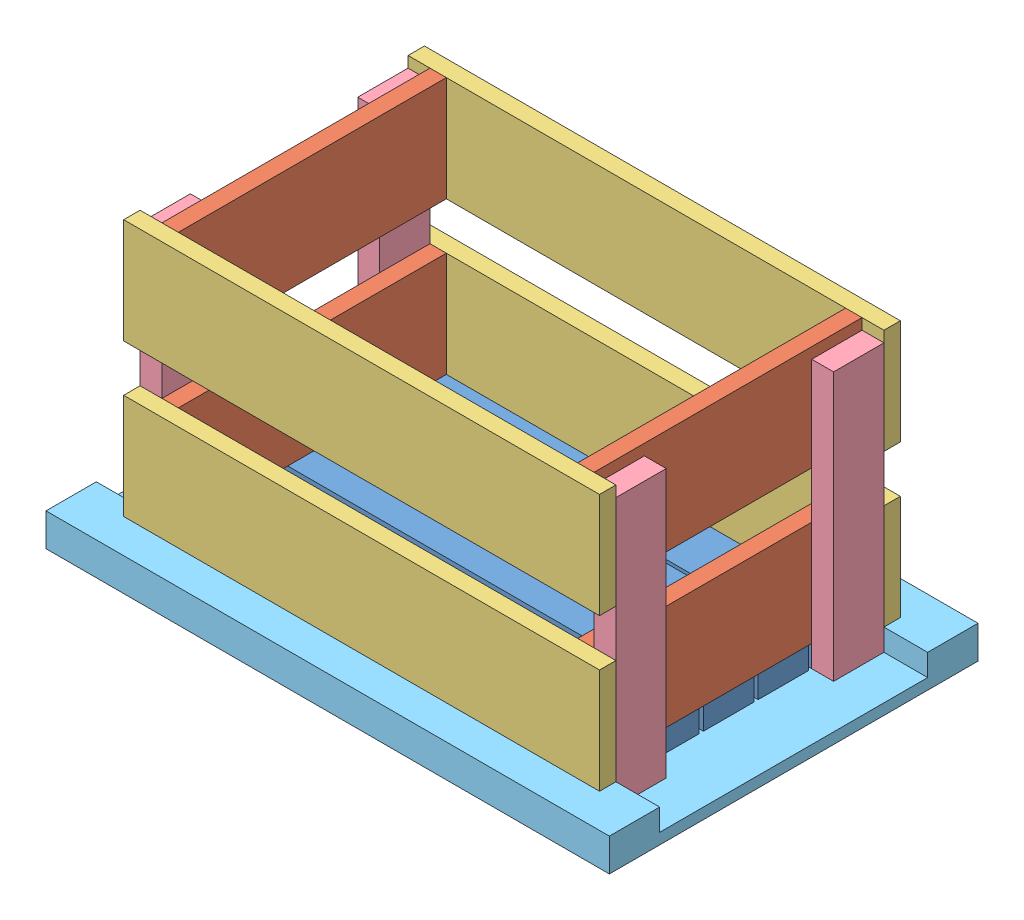
SolidWorks assembly Mal-assembly, configuration Default. Lengths in mm.
Overall size (515 265 337).
43 component instances, 6 part files, 4 mates.
Components (placement in the parent):
- Vinkasse-1: Vinkasse [Default] at (41.6987 392.7741 284.9585) size (435 265 275)
  - Bunnplank-1: Bunnplank [Default] at (0 -149 222) x (0 0 1) z (0 1 0) size (46 395 20)
  - Bunnplank-10: Bunnplank [Default] at (0 -149 23) x (0 0 1) z (0 1 0) size (46 395 20)
  - Vegg-kortside-1: Vegg-kortside [Default] at (387.5 48 245) x (0 1 0) z (-1 0 0) size (96 245 15)
  - Vegg-langside-1: Vegg-langside [Default] at (-20 48 -7.5) x (0 -1 0) z (0 0 1) size (96 435 15)
  - Vegg-langside-2: Vegg-langside [Default] at (415 48 252.5) x (0 1 0) z (0 0 1) size (96 435 15)
  - Vegg-kortside-3: Vegg-kortside [Default] at (7.5 48 0) x (0 1 0) z (1 0 0) size (96 245 15)
  - Vertikal_Stender-1: Vertikal_Stender [Default] at (405 -169 23) x (0 0 1) z (-1 0 0) size (46 255 20)
  - Vertikal_Stender-2: Vertikal_Stender [Default] at (405 -169 222) x (0 0 1) z (-1 0 0) size (46 255 20)
  - Vertikal_Stender-3: Vertikal_Stender [Default] at (-10 -169 222) x (0 0 -1) z (1 0 0) size (46 255 20)
  - Vertikal_Stender-4: Vertikal_Stender [Default] at (-10 -169 23) x (0 0 -1) z (1 0 0) size (46 255 20)
  - Vegg-kortside-5: Vegg-kortside [Default] at (7.5 -91 0) x (0 1 0) z (1 0 0) size (96 245 15)
  - Vegg-langside-3: Vegg-langside [Default] at (415 -91 252.5) x (0 1 0) z (0 0 1) size (96 435 15)
  - Vegg-langside-4: Vegg-langside [Default] at (-20 -91 -7.5) x (0 -1 0) z (0 0 1) size (96 435 15)
  - Vegg-kortside-6: Vegg-kortside [Default] at (387.5 -91 245) x (0 1 0) z (-1 0 0) size (96 245 15)
  - Dahls-1: Dahls [Default] at (41.8133 71.3082 215.5) size (59 225 59) (hidden)
  - Dahls-2: Dahls [Default] at (41.8133 71.3082 154) size (59 225 59) (hidden)
  - Dahls-3: Dahls [Default] at (41.8133 71.3082 92.5) size (59 225 59) (hidden)
  - Dahls-4: Dahls [Default] at (41.8133 71.3082 31) size (59 225 59) (hidden)
  - Dahls-5: Dahls [Default] at (103.3133 71.3082 215.5) size (59 225 59) (hidden)
  - Dahls-6: Dahls [Default] at (103.3133 71.3082 154) size (59 225 59) (hidden)
  - Dahls-7: Dahls [Default] at (103.3133 71.3082 92.5) size (59 225 59) (hidden)
  - Dahls-8: Dahls [Default] at (103.3133 71.3082 31) size (59 225 59) (hidden)
  - Dahls-9: Dahls [Default] at (164.8133 71.3082 215.5) size (59 225 59) (hidden)
  - Dahls-10: Dahls [Default] at (164.8133 71.3082 154) size (59 225 59) (hidden)
  - Dahls-11: Dahls [Default] at (164.8133 71.3082 92.5) size (59 225 59) (hidden)
  - Dahls-12: Dahls [Default] at (164.8133 71.3082 31) size (59 225 59) (hidden)
  - Dahls-13: Dahls [Default] at (226.3133 71.3082 215.5) size (59 225 59) (hidden)
  - Dahls-14: Dahls [Default] at (226.3133 71.3082 154) size (59 225 59) (hidden)
  - Dahls-15: Dahls [Default] at (226.3133 71.3082 92.5) size (59 225 59) (hidden)
  - Dahls-16: Dahls [Default] at (226.3133 71.3082 31) size (59 225 59) (hidden)
  - Dahls-17: Dahls [Default] at (287.8133 71.3082 215.5) size (59 225 59) (hidden)
  - Dahls-18: Dahls [Default] at (287.8133 71.3082 154) size (59 225 59) (hidden)
  - Dahls-19: Dahls [Default] at (287.8133 71.3082 92.5) size (59 225 59) (hidden)
  - Dahls-20: Dahls [Default] at (287.8133 71.3082 31) size (59 225 59) (hidden)
  - Dahls-21: Dahls [Default] at (349.3133 71.3082 215.5) size (59 225 59) (hidden)
  - Dahls-22: Dahls [Default] at (349.3133 71.3082 154) size (59 225 59) (hidden)
  - Dahls-23: Dahls [Default] at (349.3133 71.3082 92.5) size (59 225 59) (hidden)
  - Dahls-24: Dahls [Default] at (349.3133 71.3082 31) size (59 225 59) (hidden)
  - Bunnplank-11: Bunnplank [Default] at (0 -149 172) x (0 0 1) z (0 1 0) size (46 395 20)
  - Bunnplank-12: Bunnplank [Default] at (0 -149 122) x (0 0 1) z (0 1 0) size (46 395 20)
  - Bunnplank-13: Bunnplank [Default] at (0 -149 72) x (0 0 1) z (0 1 0) size (46 395 20)
- Part1-1: Part1 [Default] at (31.6987 223.7741 506.9585) x (0 0 1) z (0 -1 0) size (337 515 30)
Mates (geometry in assembly coordinates):
- InPlace1: in place: plane of Vinkasse-1/Vertikal_Stender-3 through (31.6987 223.7741 506.9585) normal (0 -1 0); plane of ? through (0 223.7741 0) normal (0 -1 0); moOrthogonalPlaneRef_w of Vinkasse-1/Vertikal_Stender-3 through (31.6987 223.7741 506.9585) normal (0 -1 0); plane of ? through (0 223.7741 0) normal (0 0 -1); plane of Vinkasse-1/Vertikal_Stender-3 through (31.6987 223.7741 506.9585) normal (0 -1 0); plane of ? through (0 223.7741 0) normal (-1 0 0); plane of Vinkasse-1/Vertikal_Stender-3 through (31.6987 223.7741 506.9585) normal (0 -1 0); unknown of Part1-1
- Coincident1: coincident aligned: plane of ?; plane of ?
- Coincident2: coincident aligned: moOrthogonalPlaneRef_w of Vinkasse-1/Vertikal_Stender-3 through (31.6987 223.7741 506.9585) normal (-1 0 0); plane of Copy of Part1^Mal-assembly-1 through (31.6987 223.7741 506.9585) normal (-1 0 0)
- Coincident3: coincident anti-aligned: moOrthogonalPlaneRef_w of Vinkasse-1/Vertikal_Stender-3 through (31.6987 223.7741 506.9585) normal (0 0 -1); plane of Copy of Part1^Mal-assembly-1 through (31.6987 223.7741 506.9585) normal (0 0 1)
